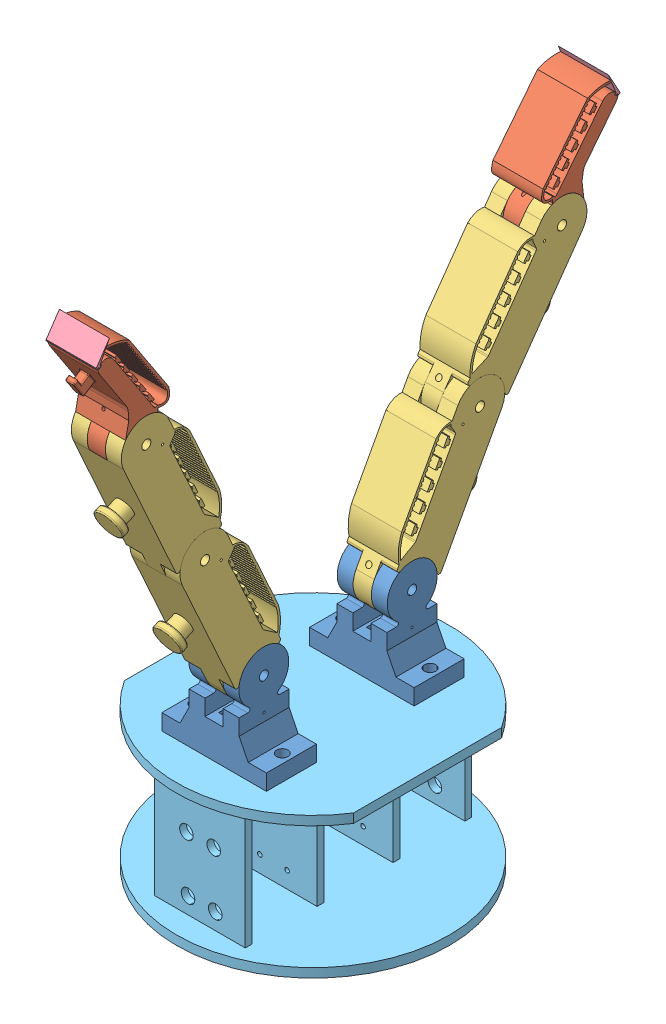
SolidWorks assembly Full_Gripper, configuration Default. Lengths in mm.
Overall size (120 289.74 319.22).
11 component instances, 5 part files, 28 mates.
Components (placement in the parent):
- Base-1: Base [Default] at (-22.0139 69.3298 106.2579) size (46 43.67 22.13)
- Gripper1-1: Gripper1 [Default] at (-22.0139 267.0724 179.4832) x (0 0.835713 0.549167) z (-1 0 0) size (65.59 109.66 22)
- Gripper2-1: Gripper2 [Default] at (-22.0139 123.4399 131.5154) x (0 -0.910262 -0.414032) z (1 0 0) size (84.5 34.69 22)
- Gripper2-2: Gripper2 [Default] at (-22.0139 180.3678 157.3612) x (0 -0.910863 -0.412708) z (1 0 0) size (84.5 34.69 22)
- FingerNail-1: FingerNail [Default] at (-33.0139 267.6636 201.1011) x (0 0.835713 0.549167) z (-1 0 0) size (5.46 9.87 22)
- Main_Base-1: Main_Base [Default] at (-22.0139 65.3298 73.7579) x (0 0 1) z (-1 0 0) size (120 62 120)
- Gripper1-2: Gripper1 [Default] at (-22.0139 257.1614 -50.5535) x (0 0.784733 -0.619834) z (1 0 0) size (65.59 109.66 22)
- FingerNail-2: FingerNail [Default] at (-11.0139 255.8685 -72.1408) x (0 0.784733 -0.619834) z (1 0 0) size (5.46 9.87 22)
- Gripper2-3: Gripper2 [Default] at (-22.0139 173.2911 -17.3474) x (0 -0.816187 0.577788) z (-1 0 0) size (84.5 34.69 22)
- Gripper2-4: Gripper2 [Default] at (-22.0139 121.6434 14.5724) x (0 -0.879311 0.476247) z (-1 0 0) size (84.5 34.69 22)
- Base-2: Base [Default] at (-22.0139 69.3298 41.2579) x (-1 0 0) z (0 0 -1) size (46 43.67 22.13)
Mates (geometry in assembly coordinates):
- Concentric10: concentric aligned: cylinder of Gripper2-1 through (-11.0139 158.8941 132.2694) axis (-1 0 0) radius 2; cylinder of Gripper2-2 through (-18.0139 158.8941 132.2694) axis (-1 0 0) radius 2
- Coincident10: coincident anti-aligned: plane of Gripper1-1 through (-18.0139 215.8231 158.0637) normal (1 0 0); plane of Gripper2-2 through (-18.0139 215.8231 158.0637) normal (-1 0 0)
- Coincident11: coincident anti-aligned: plane of Gripper2-1 through (-18.0139 158.8941 132.2694) normal (-1 0 0); plane of Gripper2-2 through (-18.0139 158.8941 132.2694) normal (1 0 0)
- Coincident12: coincident anti-aligned: plane of Gripper1-1 through (-33.0139 255.8614 177.8038) normal (0 0.74452 0.6676); plane of FingerNail-1 through (-11.0139 255.8948 177.7666) normal (0 -0.74452 -0.6676)
- Coincident13: coincident anti-aligned: line of Gripper1-1 through (-33.0139 254.9784 178.7887) axis (0 0.6676 -0.74452); line of FingerNail-1 through (-33.0139 255.8948 177.7666) axis (0 -0.6676 0.74452)
- Coincident14: coincident anti-aligned: line of Gripper1-1 through (-33.0139 256.0027 177.7962) axis (0 0.74452 0.6676); line of FingerNail-1 through (-33.0139 256.1133 177.8953) axis (0 -0.74452 -0.6676)
- Coincident15: coincident anti-aligned: plane of Gripper1-1 through (-26.0139 215.8231 158.0637) normal (-1 0 0); plane of Gripper2-2 through (-26.0139 215.8231 158.0637) normal (1 0 0)
- Concentric12: concentric aligned: cylinder of Gripper1-1 through (-11.0129 215.8231 158.0637) axis (-1 0 0) radius 2; cylinder of Gripper2-2 through (-11.0139 215.8231 158.0637) axis (-1 0 0) radius 2
- Concentric17: concentric anti-aligned: cylinder of Base-1 through (-33.0139 102.0027 106.3924) axis (1 0 0) radius 2; cylinder of Gripper2-1 through (-18.0139 102.0027 106.3924) axis (-1 0 0) radius 2
- Coincident19: coincident anti-aligned: circle of Base-1; circle of Gripper2-1
- Parallel3: parallel aligned: line of Base-1 through (0.9861 69.3298 95.2579) axis (-1 0 0); line of Main_Base-1 through (-2.0139 11.3298 123.5579) axis (-1 0 0)
- Parallel4: parallel anti-aligned: plane of Base-1 through (-33.0139 89.3298 95.2579) normal (0 0 -1); plane of Main_Base-1 through (-42.0139 11.3298 123.5579) normal (0 0 1)
- Concentric18: concentric aligned: cylinder of Base-1 through (-3.0139 69.3298 106.2579) axis (0 1 0) radius 2.5; cylinder of Main_Base-1 through (-3.0139 65.3298 106.2579) axis (0 1 0) radius 2.5
- Coincident20: coincident anti-aligned: plane of Base-1 through (-22.0139 69.3298 106.2579) normal (0 -1 0); plane of Main_Base-1 through (-22.0139 69.3298 73.7579) normal (0 1 0)
- Parallel5: parallel anti-aligned: plane of Main_Base-1 through (-22.0139 7.3298 73.7579) normal (0 -1 0)
- Concentric19: concentric aligned: cylinder of Gripper2-3 through (-26.0139 156.9597 11.3579) axis (1 0 0) radius 2; cylinder of Gripper2-4 through (-33.0139 156.9597 11.3579) axis (1 0 0) radius 2
- Coincident21: coincident anti-aligned: plane of Gripper1-2 through (-26.0139 207.9714 -24.7538) normal (-1 0 0); plane of Gripper2-3 through (-26.0139 207.9714 -24.7538) normal (1 0 0)
- Coincident22: coincident anti-aligned: plane of Gripper2-3 through (-26.0139 156.9597 11.3579) normal (-1 0 0); plane of Gripper2-4 through (-26.0139 156.9597 11.3579) normal (1 0 0)
- Coincident23: coincident anti-aligned: plane of Gripper1-2 through (-11.0139 246.1393 -47.9046) normal (0 0.683576 -0.729879); plane of FingerNail-2 through (-33.0139 246.1758 -47.8704) normal (0 -0.683576 0.729879)
- Coincident25: coincident anti-aligned: circle of Gripper2-4; circle of Base-2
- Coincident26: coincident anti-aligned: line of Gripper1-2 through (-11.0139 246.2806 -47.9092) axis (0 0.683576 -0.729879); line of FingerNail-2 through (-11.0139 246.3822 -48.0176) axis (0 -0.683576 0.729879)
- Coincident27: coincident anti-aligned: line of Gripper1-2 through (-11.0139 245.1738 -48.8088) axis (0 0.729879 0.683576); line of FingerNail-2 through (-11.0139 246.1758 -47.8704) axis (0 -0.729879 -0.683576)
- Coincident28: coincident anti-aligned: plane of Gripper1-2 through (-18.0139 207.9714 -24.7538) normal (1 0 0); plane of Gripper2-3 through (-18.0139 207.9714 -24.7538) normal (-1 0 0)
- Concentric21: concentric aligned: cylinder of Gripper1-2 through (-33.0149 207.9714 -24.7538) axis (1 0 0) radius 2; cylinder of Gripper2-3 through (-33.0139 207.9714 -24.7538) axis (1 0 0) radius 2
- Concentric22: concentric anti-aligned: cylinder of Gripper2-4 through (-26.0139 102.0027 41.1234) axis (1 0 0) radius 2; cylinder of Base-2 through (-11.0139 102.0027 41.1234) axis (-1 0 0) radius 2
- Concentric23: concentric aligned: cylinder of Main_Base-1 through (-3.0139 65.3298 41.2579) axis (0 1 0) radius 2.5; cylinder of Base-2 through (-3.0139 69.3298 41.2579) axis (0 1 0) radius 2.5
- Concentric24: concentric aligned: cylinder of Main_Base-1 through (-41.0139 65.3298 41.2579) axis (0 1 0) radius 2.5; cylinder of Base-2 through (-41.0139 69.3298 41.2579) axis (0 1 0) radius 2.5
- Coincident29: coincident anti-aligned: plane of Main_Base-1 through (-22.0139 69.3298 73.7579) normal (0 1 0); plane of Base-2 through (-22.0139 69.3298 41.2579) normal (0 -1 0)
